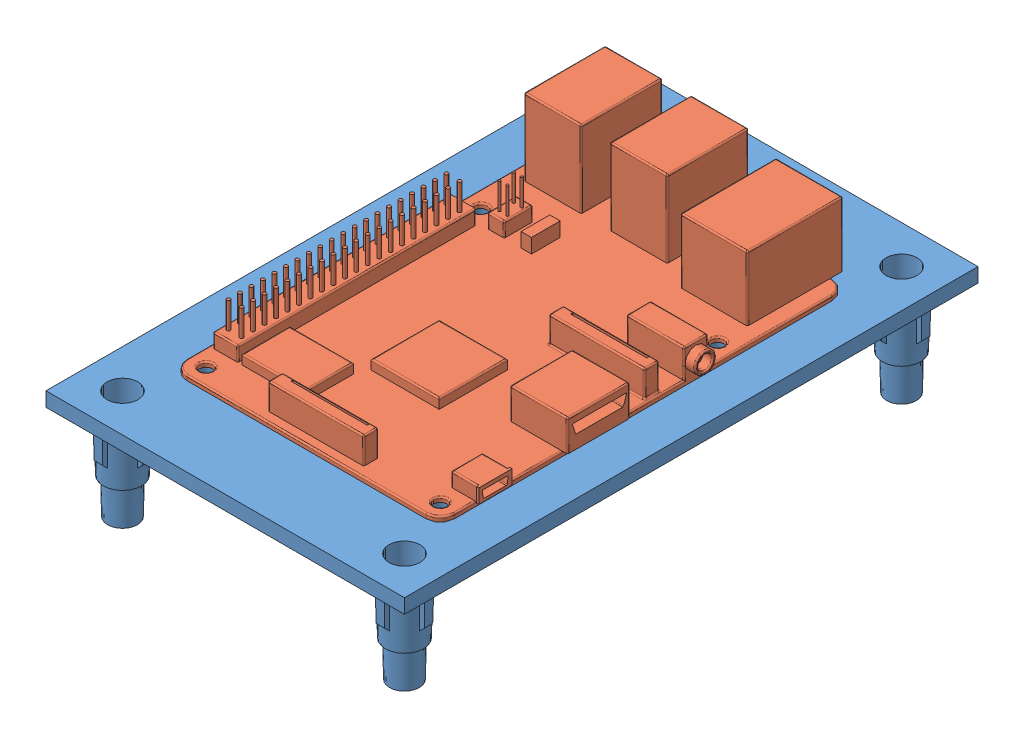
SolidWorks assembly lvl2+rasp, configuration Default. Lengths in mm.
Overall size (75 39.81 120).
2 component instances, 2 part files, 1 mates.
Components (placement in the parent):
- lvl2-1: lvl2 [Default] at (2.5282 78.8169 151.3489) x (1 0 0) z (0 0 -1) size (75 22.75 120)
- Raspberrypimodel-2: Raspberrypimodel [Default] at (37.0282 78.8825 92.3489) x (0 0 -1) z (1 0 0) size (87.5 17 58)
Mates (geometry in assembly coordinates):
- Concentric1: concentric aligned: circle of lvl2-1; circle of Raspberrypimodel-2
